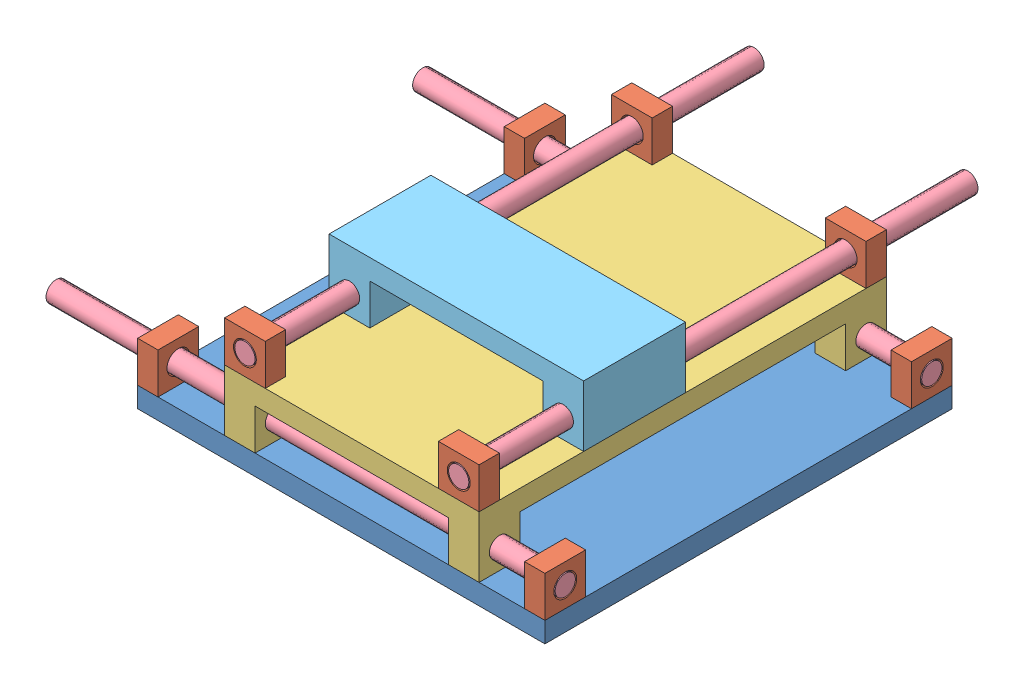
SolidWorks assembly Assem1, configuration Default. Lengths in mm.
Overall size (500 140 500).
15 component instances, 5 part files, 17 mates.
Components (placement in the parent):
- base-1: base [Default] at (132.2323 172.6409 333.7781) size (400 20 400)
- bearing-1: bearing [Default] at (332.2323 212.6409 513.7781) x (0 0 -1) z (-1 0 0) size (40 40 20)
- bearing-2: bearing [Default] at (312.2323 212.6409 153.7781) x (0 0 1) z (1 0 0) size (40 40 20)
- bearing-3: bearing [Default] at (-47.7677 212.6409 513.7781) x (0 0 -1) z (-1 0 0) size (40 40 20)
- bearing-4: bearing [Default] at (-67.7677 212.6409 153.7781) x (0 0 1) z (1 0 0) size (40 40 20)
- cross slide-1: cross slide [Default] at (142.5831 252.6409 333.7781) x (0 0 1) z (1 0 0) size (400 60 250)
- ledad screw-3: ledad screw [Default] at (-167.7677 212.6409 513.7781) x (0 0 -1) z (1 0 0) size (20 20 500)
- ledad screw-4: ledad screw [Default] at (332.2323 212.6409 153.7781) x (0 0 1) z (-1 0 0) size (20 20 500)
- bearing-5: bearing [Default] at (247.5831 272.6409 513.7781) size (40 40 20)
- bearing-6: bearing [Default] at (247.5831 272.6409 133.7781) size (40 40 20)
- bearing-7: bearing [Default] at (37.5831 272.6409 533.7781) x (-1 0 0) z (0 0 -1) size (40 40 20)
- bearing-8: bearing [Default] at (37.5831 272.6409 153.7781) x (-1 0 0) z (0 0 -1) size (40 40 20)
- ledad screw-5: ledad screw [Default] at (37.5831 272.6409 33.7781) x (0.999997 0.002298 0) z (0 0 1) size (20 20 500)
- ledad screw-6: ledad screw [Default] at (247.5831 272.6409 533.7781) x (-0.999997 0.002298 0) z (0 0 -1) size (20 20 500)
- tool base-1: tool base [Default] at (142.5831 312.6409 431.0882) x (1 0 0) z (0 0 -1) size (250 60 100)
Mates (geometry in assembly coordinates):
- Concentric1: concentric anti-aligned: cylinder of bearing-1 through (300.4151 234.1682 504.9637) axis (1 0 0) radius 11.2192; cylinder of ? through (332.2323 234.1682 504.9637) axis (-1 0 0) radius 10
- Coincident5: coincident aligned: plane of base-1 through (332.2323 192.6409 533.7781) normal (1 0 0); plane of bearing-1 through (332.2323 212.6409 513.7781) normal (1 0 0)
- Coincident6: coincident aligned: plane of base-1 through (-67.7677 192.6409 533.7781) normal (0 0 1); plane of bearing-1 through (312.2323 232.6409 533.7781) normal (0 0 1)
- Coincident7: coincident anti-aligned: plane of base-1 through (132.2323 192.6409 333.7781) normal (0 1 0); plane of bearing-1 through (312.2323 192.6409 533.7781) normal (0 -1 0)
- Concentric4: concentric anti-aligned: cylinder of bearing-4 through (-47.7677 212.6409 153.7781) axis (-1 0 0) radius 11.2192; cylinder of cross slide-1 through (237.5831 212.6409 153.7781) axis (1 0 0) radius 10
- Concentric5: concentric aligned: cylinder of bearing-3 through (-67.7677 212.6409 513.7781) axis (1 0 0) radius 11.2192; cylinder of cross slide-1 through (237.5831 212.6409 513.7781) axis (1 0 0) radius 10
- Concentric6: concentric anti-aligned: cylinder of bearing-1 through (312.2323 212.6409 513.7781) axis (1 0 0) radius 11.2192; cylinder of ledad screw-3 through (332.2323 212.6409 513.7781) axis (-1 0 0) radius 10
- Coincident8: coincident aligned: plane of bearing-1 through (332.2323 212.6409 513.7781) normal (1 0 0); plane of ledad screw-3 through (332.2323 212.6409 513.7781) normal (1 0 0)
- Concentric7: concentric anti-aligned: cylinder of bearing-2 through (332.2323 212.6409 153.7781) axis (-1 0 0) radius 11.2192; cylinder of ledad screw-4 through (-167.7677 212.6409 153.7781) axis (1 0 0) radius 10
- Coincident9: coincident aligned: plane of bearing-2 through (332.2323 212.6409 153.7781) normal (1 0 0); plane of ledad screw-4 through (332.2323 212.6409 153.7781) normal (1 0 0)
- Coincident10: coincident aligned: plane of cross slide-1 through (267.5831 232.6409 133.7781) normal (1 0 0); plane of bearing-5 through (267.5831 252.6409 533.7781) normal (1 0 0)
- Coincident11: coincident: line of cross slide-1 through (237.5831 232.6409 533.7781) axis (0 -1 0); plane of bearing-5 through (247.5831 272.6409 533.7781) normal (0 0 1)
- Coincident12: coincident anti-aligned: plane of cross slide-1 through (142.5831 252.6409 333.7781) normal (0 1 0); plane of bearing-5 through (227.5831 252.6409 533.7781) normal (0 -1 0)
- Concentric8: concentric anti-aligned: cylinder of bearing-7 through (37.5831 272.6409 513.7781) axis (0 0 1) radius 11.2192; cylinder of ledad screw-5 through (37.5831 272.6409 533.7781) axis (0 0 -1) radius 10
- Coincident13: coincident aligned: plane of bearing-7 through (37.5831 272.6409 533.7781) normal (0 0 1); plane of ledad screw-5 through (37.5831 272.6409 533.7781) normal (0 0 1)
- Coincident14: coincident aligned: cylinder of ledad screw-5 through (37.5831 272.6409 533.7781) axis (0 0 -1) radius 10; circle of tool base-1
- Concentric9: concentric anti-aligned: cylinder of ledad screw-6 through (247.5831 272.6409 33.7781) axis (0 0 1) radius 10; cylinder of tool base-1 through (247.5831 272.6409 461.0882) axis (0 0 -1) radius 10
